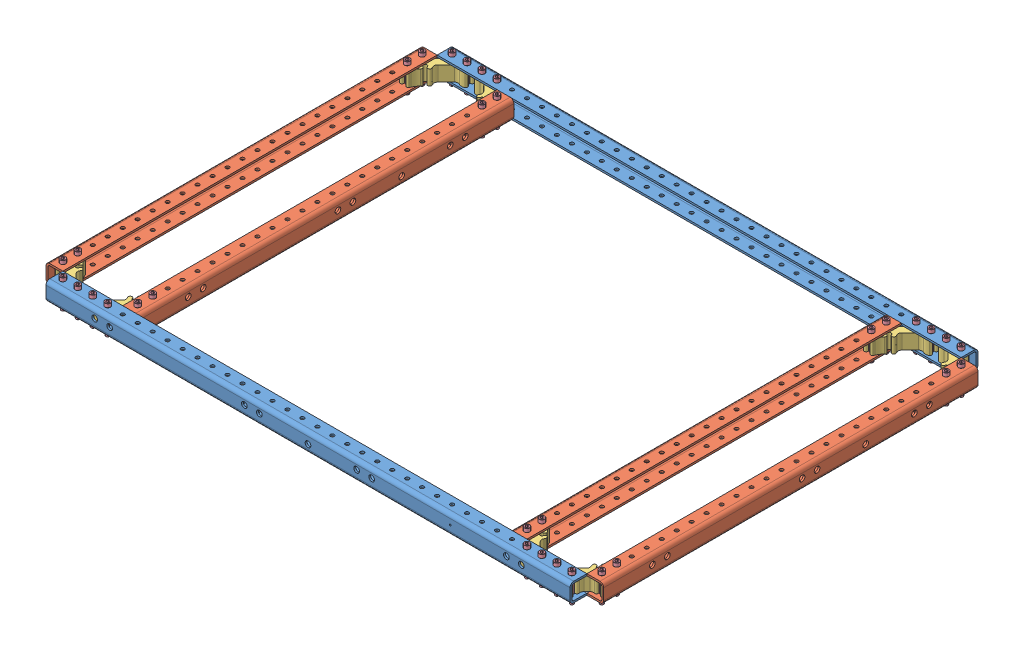
SolidWorks assembly C-Base-Triangle-Mounts-no-bracket-WIDE, configuration Default. Lengths in mm.
Overall size (966.2 50.8 712.2).
78 component instances, 5 part files, 32 mates.
Components (placement in the parent):
- C channel Outer-1: C channel Outer [Default] at (0 0 -317.4979) x (0 -1 0) z (0 0 1) size (31.75 889 28.57)
- Short C channel-1: Short C channel [for WIDE frame] at (444.5 0 -25.4) x (0 1 0) z (-1 0 0) size (31.75 635 28.57)
- Corner_Extrusion-2: Corner_Extrusion [Default] at (437.7662 0 -310.765) x (-0.707157 0 -0.707057) z (0 -1 0) size (90.51 36.63 25.4)
- SHCS_1-6: SHCS_1 [1.75] at (457.2 -3.175 -279.4) x (0 -1 0) z (0 0 -1) size (50.8 9.4 9.4)
- SHCS_1-7: SHCS_1 [1.75] at (457.2 -3.175 -304.8) x (0 -1 0) z (0 0 -1) size (50.8 9.4 9.4)
- SHCS_1-8: SHCS_1 [1.75] at (431.8 -3.175 -330.1979) x (0 -1 0) z (0 0 -1) size (50.8 9.4 9.4)
- SHCS_1-9: SHCS_1 [1.75] at (406.4 -3.175 -330.1979) x (0 -1 0) z (0 0 -1) size (50.8 9.4 9.4)
- Quarer20_Nut-5: Quarer20_Nut [Default] at (457.2 -18.8595 -279.4) x (0.837169 0 -0.546944) z (0.546944 0 0.837169) size (14.11 5.97 11.11)
- Quarer20_Nut-6: Quarer20_Nut [Default] at (457.2 -18.8595 -304.8) x (0.837169 0 -0.546944) z (0.546944 0 0.837169) size (14.11 5.97 11.11)
- Quarer20_Nut-9: Quarer20_Nut [Default] at (406.4 -18.8595 -330.1979) x (0.837169 0 -0.546944) z (0.546944 0 0.837169) size (14.11 5.97 11.11)
- Quarer20_Nut-12: Quarer20_Nut [Default] at (431.8 -18.8595 -330.1979) x (0.837169 0 -0.546944) z (0.546944 0 0.837169) size (14.11 5.97 11.11)
- C channel Outer-4: C channel Outer [Default] at (0 0 317.4979) x (0 -1 0) z (0 0 -1) size (31.75 889 28.57)
- Short C channel-3: Short C channel [for WIDE frame] at (-444.5 0 25.4) x (0 1 0) z (1 0 0) size (31.75 635 28.57)
- SHCS_1-18: SHCS_1 [1.75] at (330.2 -3.175 -279.4) x (0 -1 0) z (0 0 1) size (50.8 9.4 9.4)
- SHCS_1-19: SHCS_1 [1.75] at (330.2 -3.175 -304.8) x (0 -1 0) z (0 0 1) size (50.8 9.4 9.4)
- SHCS_1-20: SHCS_1 [1.75] at (355.6 -3.175 -330.1979) x (0 -1 0) z (0 0 1) size (50.8 9.4 9.4)
- SHCS_1-21: SHCS_1 [1.75] at (381 -3.175 -330.1979) x (0 -1 0) z (0 0 1) size (50.8 9.4 9.4)
- Quarer20_Nut-21: Quarer20_Nut [Default] at (330.2 -18.8595 -279.4) x (-0.837169 0 -0.546944) z (0.546944 0 -0.837169) size (14.11 5.97 11.11)
- Quarer20_Nut-22: Quarer20_Nut [Default] at (330.2 -18.8595 -304.8) x (-0.837169 0 -0.546944) z (0.546944 0 -0.837169) size (14.11 5.97 11.11)
- Quarer20_Nut-23: Quarer20_Nut [Default] at (381 -18.8595 -330.1979) x (-0.837169 0 -0.546944) z (0.546944 0 -0.837169) size (14.11 5.97 11.11)
- Quarer20_Nut-24: Quarer20_Nut [Default] at (355.6 -18.8595 -330.1979) x (-0.837169 0 -0.546944) z (0.546944 0 -0.837169) size (14.11 5.97 11.11)
- Corner_Extrusion-5: Corner_Extrusion [Default] at (349.6338 0 -310.765) x (0.707157 0 -0.707057) z (0 1 0) size (90.51 36.63 25.4)
- SHCS_1-30: SHCS_1 [1.75] at (330.2 -3.175 279.4) x (0 -1 0) z (0 0 1) size (50.8 9.4 9.4)
- SHCS_1-31: SHCS_1 [1.75] at (330.2 -3.175 304.8) x (0 -1 0) z (0 0 1) size (50.8 9.4 9.4)
- SHCS_1-32: SHCS_1 [1.75] at (355.6 -3.175 330.1979) x (0 -1 0) z (0 0 1) size (50.8 9.4 9.4)
- SHCS_1-33: SHCS_1 [1.75] at (381 -3.175 330.1979) x (0 -1 0) z (0 0 1) size (50.8 9.4 9.4)
- Quarer20_Nut-33: Quarer20_Nut [Default] at (330.2 -18.8595 279.4) x (-0.837169 0 0.546944) z (-0.546944 0 -0.837169) size (14.11 5.97 11.11)
- Quarer20_Nut-34: Quarer20_Nut [Default] at (330.2 -18.8595 304.8) x (-0.837169 0 0.546944) z (-0.546944 0 -0.837169) size (14.11 5.97 11.11)
- Quarer20_Nut-35: Quarer20_Nut [Default] at (381 -18.8595 330.1979) x (-0.837169 0 0.546944) z (-0.546944 0 -0.837169) size (14.11 5.97 11.11)
- Quarer20_Nut-36: Quarer20_Nut [Default] at (355.6 -18.8595 330.1979) x (-0.837169 0 0.546944) z (-0.546944 0 -0.837169) size (14.11 5.97 11.11)
- Corner_Extrusion-8: Corner_Extrusion [Default] at (349.6338 0 310.765) x (0.707157 0 0.707057) z (0 -1 0) size (90.51 36.63 25.4)
- SHCS_1-34: SHCS_1 [1.75] at (457.2 -3.175 279.4) x (0 -1 0) z (0 0 -1) size (50.8 9.4 9.4)
- SHCS_1-35: SHCS_1 [1.75] at (457.2 -3.175 304.8) x (0 -1 0) z (0 0 -1) size (50.8 9.4 9.4)
- SHCS_1-36: SHCS_1 [1.75] at (431.8 -3.175 330.1979) x (0 -1 0) z (0 0 -1) size (50.8 9.4 9.4)
- SHCS_1-37: SHCS_1 [1.75] at (406.4 -3.175 330.1979) x (0 -1 0) z (0 0 -1) size (50.8 9.4 9.4)
- Corner_Extrusion-9: Corner_Extrusion [Default] at (437.7662 0 310.765) x (-0.707157 0 0.707057) z (0 1 0) size (90.51 36.63 25.4)
- Quarer20_Nut-37: Quarer20_Nut [Default] at (457.2 -18.8595 279.4) x (0.837169 0 0.546944) z (-0.546944 0 0.837169) size (14.11 5.97 11.11)
- Quarer20_Nut-38: Quarer20_Nut [Default] at (457.2 -18.8595 304.8) x (0.837169 0 0.546944) z (-0.546944 0 0.837169) size (14.11 5.97 11.11)
- Quarer20_Nut-39: Quarer20_Nut [Default] at (431.8 -18.8595 330.1979) x (0.837169 0 0.546944) z (-0.546944 0 0.837169) size (14.11 5.97 11.11)
- Quarer20_Nut-40: Quarer20_Nut [Default] at (406.4 -18.8595 330.1979) x (0.837169 0 0.546944) z (-0.546944 0 0.837169) size (14.11 5.97 11.11)
- SHCS_1-38: SHCS_1 [1.75] at (-330.2 -3.175 -279.4) x (0 -1 0) z (0 0 -1) size (50.8 9.4 9.4)
- SHCS_1-39: SHCS_1 [1.75] at (-330.2 -3.175 -304.8) x (0 -1 0) z (0 0 -1) size (50.8 9.4 9.4)
- SHCS_1-40: SHCS_1 [1.75] at (-355.6 -3.175 -330.1979) x (0 -1 0) z (0 0 -1) size (50.8 9.4 9.4)
- SHCS_1-41: SHCS_1 [1.75] at (-381 -3.175 -330.1979) x (0 -1 0) z (0 0 -1) size (50.8 9.4 9.4)
- Quarer20_Nut-41: Quarer20_Nut [Default] at (-330.2 -18.8595 -279.4) x (0.837169 0 -0.546944) z (0.546944 0 0.837169) size (14.11 5.97 11.11)
- Quarer20_Nut-42: Quarer20_Nut [Default] at (-330.2 -18.8595 -304.8) x (0.837169 0 -0.546944) z (0.546944 0 0.837169) size (14.11 5.97 11.11)
- Quarer20_Nut-43: Quarer20_Nut [Default] at (-381 -18.8595 -330.1979) x (0.837169 0 -0.546944) z (0.546944 0 0.837169) size (14.11 5.97 11.11)
- Quarer20_Nut-44: Quarer20_Nut [Default] at (-355.6 -18.8595 -330.1979) x (0.837169 0 -0.546944) z (0.546944 0 0.837169) size (14.11 5.97 11.11)
- Corner_Extrusion-10: Corner_Extrusion [Default] at (-349.6338 0 -310.765) x (-0.707157 0 -0.707057) z (0 -1 0) size (90.51 36.63 25.4)
- SHCS_1-42: SHCS_1 [1.75] at (-330.2 -3.175 279.4) x (0 -1 0) z (0 0 -1) size (50.8 9.4 9.4)
- SHCS_1-43: SHCS_1 [1.75] at (-330.2 -3.175 304.8) x (0 -1 0) z (0 0 -1) size (50.8 9.4 9.4)
- SHCS_1-44: SHCS_1 [1.75] at (-355.6 -3.175 330.1979) x (0 -1 0) z (0 0 -1) size (50.8 9.4 9.4)
- SHCS_1-45: SHCS_1 [1.75] at (-381 -3.175 330.1979) x (0 -1 0) z (0 0 -1) size (50.8 9.4 9.4)
- Quarer20_Nut-45: Quarer20_Nut [Default] at (-330.2 -18.8595 279.4) x (0.837169 0 0.546944) z (-0.546944 0 0.837169) size (14.11 5.97 11.11)
- Quarer20_Nut-46: Quarer20_Nut [Default] at (-330.2 -18.8595 304.8) x (0.837169 0 0.546944) z (-0.546944 0 0.837169) size (14.11 5.97 11.11)
- Quarer20_Nut-47: Quarer20_Nut [Default] at (-381 -18.8595 330.1979) x (0.837169 0 0.546944) z (-0.546944 0 0.837169) size (14.11 5.97 11.11)
- Quarer20_Nut-48: Quarer20_Nut [Default] at (-355.6 -18.8595 330.1979) x (0.837169 0 0.546944) z (-0.546944 0 0.837169) size (14.11 5.97 11.11)
- Corner_Extrusion-11: Corner_Extrusion [Default] at (-349.6338 0 310.765) x (-0.707157 0 0.707057) z (0 1 0) size (90.51 36.63 25.4)
- SHCS_1-46: SHCS_1 [1.75] at (-457.2 -3.175 279.4) x (0 -1 0) z (0 0 1) size (50.8 9.4 9.4)
- SHCS_1-47: SHCS_1 [1.75] at (-457.2 -3.175 304.8) x (0 -1 0) z (0 0 1) size (50.8 9.4 9.4)
- SHCS_1-48: SHCS_1 [1.75] at (-431.8 -3.175 330.1979) x (0 -1 0) z (0 0 1) size (50.8 9.4 9.4)
- SHCS_1-49: SHCS_1 [1.75] at (-406.4 -3.175 330.1979) x (0 -1 0) z (0 0 1) size (50.8 9.4 9.4)
- Corner_Extrusion-12: Corner_Extrusion [Default] at (-437.7662 0 310.765) x (0.707157 0 0.707057) z (0 -1 0) size (90.51 36.63 25.4)
- Quarer20_Nut-49: Quarer20_Nut [Default] at (-457.2 -18.8595 279.4) x (-0.837169 0 0.546944) z (-0.546944 0 -0.837169) size (14.11 5.97 11.11)
- Quarer20_Nut-50: Quarer20_Nut [Default] at (-457.2 -18.8595 304.8) x (-0.837169 0 0.546944) z (-0.546944 0 -0.837169) size (14.11 5.97 11.11)
- Quarer20_Nut-51: Quarer20_Nut [Default] at (-431.8 -18.8595 330.1979) x (-0.837169 0 0.546944) z (-0.546944 0 -0.837169) size (14.11 5.97 11.11)
- Quarer20_Nut-52: Quarer20_Nut [Default] at (-406.4 -18.8595 330.1979) x (-0.837169 0 0.546944) z (-0.546944 0 -0.837169) size (14.11 5.97 11.11)
- SHCS_1-50: SHCS_1 [1.75] at (-457.2 -3.175 -304.8) x (0 -1 0) z (0 0 1) size (50.8 9.4 9.4)
- Corner_Extrusion-13: Corner_Extrusion [Default] at (-437.7662 0 -310.765) x (0.707157 0 -0.707057) z (0 1 0) size (90.51 36.63 25.4)
- SHCS_1-51: SHCS_1 [1.75] at (-431.8 -3.175 -330.1979) x (0 -1 0) z (0 0 1) size (50.8 9.4 9.4)
- SHCS_1-52: SHCS_1 [1.75] at (-406.4 -3.175 -330.1979) x (0 -1 0) z (0 0 1) size (50.8 9.4 9.4)
- SHCS_1-53: SHCS_1 [1.75] at (-457.2 -3.175 -279.4) x (0 -1 0) z (0 0 1) size (50.8 9.4 9.4)
- Quarer20_Nut-53: Quarer20_Nut [Default] at (-457.2 -18.8595 -279.4) x (-0.837169 0 -0.546944) z (0.546944 0 -0.837169) size (14.11 5.97 11.11)
- Quarer20_Nut-54: Quarer20_Nut [Default] at (-457.2 -18.8595 -304.8) x (-0.837169 0 -0.546944) z (0.546944 0 -0.837169) size (14.11 5.97 11.11)
- Quarer20_Nut-55: Quarer20_Nut [Default] at (-431.8 -18.8595 -330.1979) x (-0.837169 0 -0.546944) z (0.546944 0 -0.837169) size (14.11 5.97 11.11)
- Quarer20_Nut-56: Quarer20_Nut [Default] at (-406.4 -18.8595 -330.1979) x (-0.837169 0 -0.546944) z (0.546944 0 -0.837169) size (14.11 5.97 11.11)
- Short C channel-8: Short C channel [for WIDE frame] at (342.9 0 25.4) x (0 1 0) z (1 0 0) size (31.75 635 28.57)
- Short C channel-10: Short C channel [for WIDE frame] at (-342.9 0 -25.4) x (0 1 0) z (-1 0 0) size (31.75 635 28.57)
Mates (geometry in assembly coordinates):
- Coincident4: coincident aligned: line of Short C channel-1 through (0 -25.4 0) axis (1 0 0); plane of assembly through (0 0 0) normal (0 1 0)
- Symmetric1: symmetric aligned: plane of Short C channel-1 through (444.5 15.875 -317.5) normal (0 0 -1); plane of Short C channel-1 through (466.725 -9.525 317.5) normal (0 0 1); plane of assembly through (0 0 0) normal (0 0 1)
- Coincident28: coincident aligned: plane of C channel Outer-1 through (444.5 -15.875 -317.4979) normal (0 -1 0); plane of Short C channel-1 through (466.725 -15.875 -368.3) normal (0 -1 0)
- Coincident29: coincident anti-aligned: plane of C channel Outer-1 through (444.5 9.525 -339.7229) normal (1 0 0); plane of Short C channel-1 through (444.5 12.7 -368.3) normal (-1 0 0)
- Coincident30: coincident aligned: unknown of C channel Outer-1; plane of assembly through (0 0 0) normal (1 0 0)
- Concentric24: concentric anti-aligned: cylinder of Short C channel-1 through (457.2 -15.875 -279.4) axis (0 -1 0) radius 3.175; cylinder of SHCS_1-6 through (457.2 21.3298 -279.4) axis (0 1 0) radius 3.1115
- Coincident32: coincident anti-aligned: plane of Short C channel-1 through (444.5 15.875 -368.3) normal (0 1 0); plane of SHCS_1-6 through (454.0885 15.875 -279.4) normal (0 -1 0)
- Concentric26: concentric anti-aligned: cylinder of Short C channel-1 through (457.2 -15.875 -304.8) axis (0 -1 0) radius 3.175; cylinder of SHCS_1-7 through (457.2 21.3298 -304.8) axis (0 1 0) radius 3.1115
- Coincident34: coincident anti-aligned: plane of Short C channel-1 through (444.5 15.875 -368.3) normal (0 1 0); plane of SHCS_1-7 through (454.0885 15.875 -304.8) normal (0 -1 0)
- Concentric28: concentric anti-aligned: cylinder of C channel Outer-1 through (431.8 19.125 -330.1979) axis (0 -1 0) radius 3.175; cylinder of SHCS_1-8 through (431.8 21.3298 -330.1979) axis (0 1 0) radius 3.1115
- Coincident36: coincident anti-aligned: plane of C channel Outer-1 through (444.5 15.875 -339.7229) normal (0 1 0); plane of SHCS_1-8 through (428.6885 15.875 -330.1979) normal (0 -1 0)
- Concentric30: concentric anti-aligned: cylinder of C channel Outer-1 through (406.4 19.125 -330.1979) axis (0 -1 0) radius 3.175; cylinder of SHCS_1-9 through (406.4 21.3298 -330.1979) axis (0 1 0) radius 3.1115
- Coincident38: coincident anti-aligned: plane of C channel Outer-1 through (444.5 15.875 -339.7229) normal (0 1 0); plane of SHCS_1-9 through (403.2885 15.875 -330.1979) normal (0 -1 0)
- Concentric32: concentric aligned: cylinder of Short C channel-1 through (457.2 -15.875 -279.4) axis (0 -1 0) radius 3.175; cylinder of Quarer20_Nut-5 through (457.2 -15.875 -279.4) axis (0 -1 0) radius 3.1115
- Coincident40: coincident anti-aligned: plane of Short C channel-1 through (466.725 -15.875 -368.3) normal (0 -1 0); plane of Quarer20_Nut-5 through (451.4755 -15.875 -282.297) normal (0 1 0)
- Concentric34: concentric aligned: cylinder of Short C channel-1 through (457.2 -15.875 -304.8) axis (0 -1 0) radius 3.175; cylinder of Quarer20_Nut-6 through (457.2 -15.875 -304.8) axis (0 -1 0) radius 3.1115
- Coincident42: coincident anti-aligned: plane of Short C channel-1 through (466.725 -15.875 -368.3) normal (0 -1 0); plane of Quarer20_Nut-6 through (451.4755 -15.875 -307.697) normal (0 1 0)
- Concentric36: concentric aligned: cylinder of C channel Outer-1 through (406.4 19.125 -330.1979) axis (0 -1 0) radius 3.175; cylinder of Quarer20_Nut-9 through (406.4 -15.875 -330.1979) axis (0 -1 0) radius 3.1115
- Coincident44: coincident anti-aligned: plane of C channel Outer-1 through (444.5 -15.875 -317.4979) normal (0 -1 0); plane of Quarer20_Nut-9 through (400.6755 -15.875 -333.0949) normal (0 1 0)
- Concentric38: concentric aligned: cylinder of C channel Outer-1 through (431.8 19.125 -330.1979) axis (0 -1 0) radius 3.175; cylinder of Quarer20_Nut-12 through (431.8 -15.875 -330.1979) axis (0 -1 0) radius 3.1115
- Coincident46: coincident anti-aligned: plane of C channel Outer-1 through (444.5 -15.875 -317.4979) normal (0 -1 0); plane of Quarer20_Nut-12 through (426.0755 -15.875 -333.0949) normal (0 1 0)
- Hinge5: hinge anti-aligned: cylinder of Corner_Extrusion-2 through (457.2 -12.7 -279.4) axis (0 1 0) radius 3.302; cylinder of Short C channel-1 through (457.2 -15.875 -279.4) axis (0 -1 0) radius 3.175; plane of Short C channel-1 through (444.5 -12.7 -368.3) normal (0 1 0); plane of Corner_Extrusion-2 through (431.8 -12.7 -330.1997) normal (0 -1 0)
- Concentric39: concentric anti-aligned: cylinder of C channel Outer-1 through (406.4 19.125 -330.1979) axis (0 -1 0) radius 3.175; cylinder of Corner_Extrusion-2 through (406.4 -12.7 -330.1979) axis (0 1 0) radius 3.302
- Lock9: lock: unknown of ?; unknown of ?
- Lock11: lock: unknown of ?; unknown of ?
- Lock12: lock: unknown of ?; unknown of ?
- Lock13: lock: unknown of ?; unknown of ?
- Lock14: lock: unknown of ?; unknown of ?
- Lock15: lock: unknown of ?; unknown of ?
- Lock16: lock: unknown of ?; unknown of ?
- Lock17: lock: unknown of ?; unknown of ?
- Plane1: unknown = 50.8 mm: plane of Short C channel-1 through (444.5 12.7 -368.3) normal (-1 0 0)
